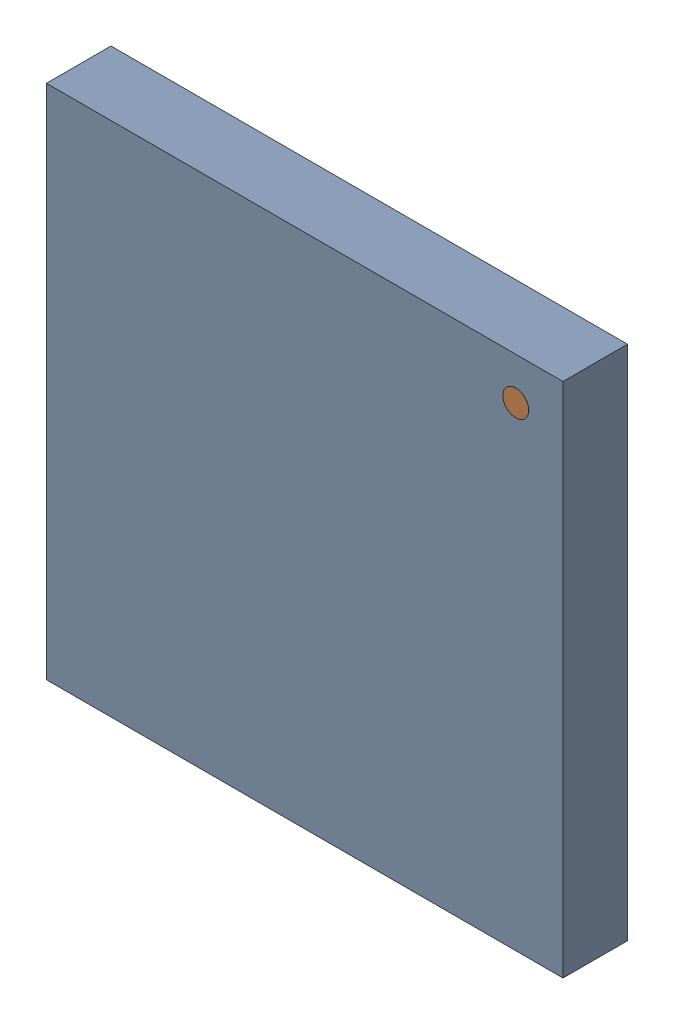
SolidWorks assembly U2, configuration ﾃﾞﾌｫﾙﾄ. Lengths in mm.
Overall size (8 8 1).
4 component instances, 2 part files, 0 mates.
Components (placement in the parent):
- 6641437328-1: 6641437328 [ﾃﾞﾌｫﾙﾄ] at (8.169 10.388 0) size (8 8 1)
  - Extruded-26-1: Extruded-26 [ﾃﾞﾌｫﾙﾄ] at origin size (8 8 1)
- 6641437008-1: 6641437008 [ﾃﾞﾌｫﾙﾄ] at (11.439 13.736 0) x (0 -1 0) z (0 0 1) size (0.4 0.4 1)
  - Cylinder-27-1: Cylinder-27 [ﾃﾞﾌｫﾙﾄ] at origin size (0.4 0.4 1)
